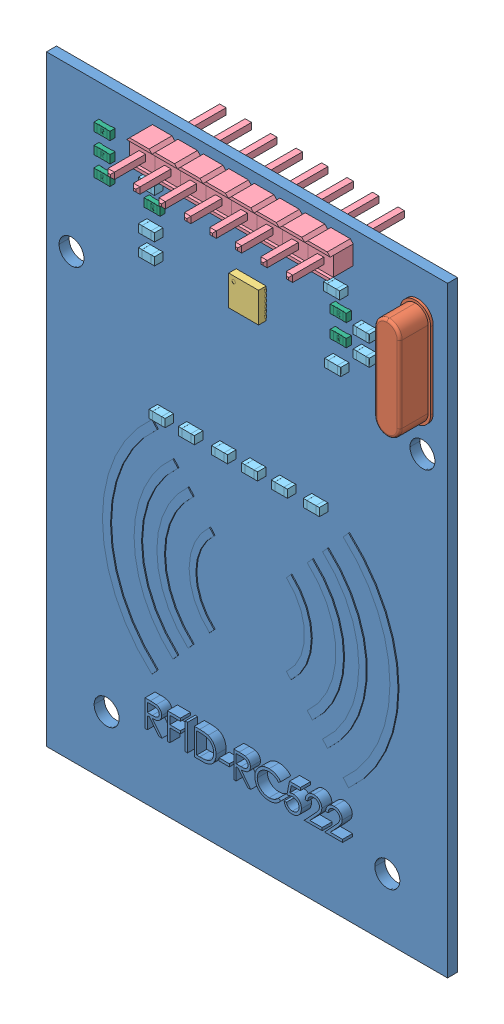
SolidWorks assembly RFID.STEP, configuration Default. Lengths in mm.
Overall size (40 60 11.55).
23 component instances, 6 part files, 0 mates.
Components (placement in the parent):
- Part1^RFID.STEP-1: Part1^RFID.STEP [Default] at (-16.3439 30.7712 59.45) size (40 60 2) (virtual)
- Part10^RFID.STEP-1: Part10^RFID.STEP [Default] at (20.709 20.1029 60.45) x (0 1 0) z (0 0 1) size (10.67 3.05 5.63) (virtual)
- User Library-S-PWSON-N12^RFID.STEP-1: User Library-S-PWSON-N12^RFID.STEP [Default] at (4.1233 20.047 60.45) x (1 0 0) z (0 -1 0) size (3 0.8 3) (virtual)
- User Library-Header_Male_8Pin^RFID.STEP-1: User Library-Header_Male_8Pin^RFID.STEP [Default] at (12.9823 28.5305 62.74) x (-1 0 0) z (0 0 -1) size (20.33 2.5 11.55) (virtual)
- User Library-SMD Ceramic Capacitors_0603 (1608)_CH.STEP-1: User Library-SMD Ceramic Capacitors_0603 (1608)_CH.STEP [Default] at (-3.9959 5.9247 60.9127) size (1.68 0.88 0.93)
- User Library-SMD Ceramic Capacitors_0603 (1608)_CH.STEP-2: User Library-SMD Ceramic Capacitors_0603 (1608)_CH.STEP [Default] at (-1.0806 5.9034 60.9127) size (1.68 0.88 0.93)
- User Library-SMD Ceramic Capacitors_0603 (1608)_CH.STEP-3: User Library-SMD Ceramic Capacitors_0603 (1608)_CH.STEP [Default] at (2.2282 5.9089 60.9127) size (1.68 0.88 0.93)
- User Library-SMD Ceramic Capacitors_0603 (1608)_CH.STEP-4: User Library-SMD Ceramic Capacitors_0603 (1608)_CH.STEP [Default] at (5.214 5.921 60.9127) size (1.68 0.88 0.93)
- User Library-SMD Ceramic Capacitors_0603 (1608)_CH.STEP-5: User Library-SMD Ceramic Capacitors_0603 (1608)_CH.STEP [Default] at (8.193 5.9188 60.9127) size (1.68 0.88 0.93)
- User Library-SMD Ceramic Capacitors_0603 (1608)_CH.STEP-6: User Library-SMD Ceramic Capacitors_0603 (1608)_CH.STEP [Default] at (11.3855 5.9271 60.9127) size (1.68 0.88 0.93)
- User Library-SMD Ceramic Capacitors_0603 (1608)_CH.STEP-7: User Library-SMD Ceramic Capacitors_0603 (1608)_CH.STEP [Default] at (16.3593 23.3789 60.9127) size (1.68 0.88 0.93)
- User Library-SMD Ceramic Capacitors_0603 (1608)_CH.STEP-8: User Library-SMD Ceramic Capacitors_0603 (1608)_CH.STEP [Default] at (16.3593 21.3117 60.9127) size (1.68 0.88 0.93)
- User Library-SMD Ceramic Capacitors_0603 (1608)_CH.STEP-9: User Library-SMD Ceramic Capacitors_0603 (1608)_CH.STEP [Default] at (13.4136 25.6528 60.9127) size (1.68 0.88 0.93)
- User Library-SMD Ceramic Capacitors_0603 (1608)_CH.STEP-10: User Library-SMD Ceramic Capacitors_0603 (1608)_CH.STEP [Default] at (13.517 19.0895 60.9127) size (1.68 0.88 0.93)
- Part8^RFID.STEP-1: Part8^RFID.STEP [Default] at (13.517 23.4826 60.704) size (1.6 0.81 0.51) (virtual)
- Part8^RFID.STEP-2: Part8^RFID.STEP [Default] at (13.517 21.3121 60.704) size (1.6 0.81 0.51) (virtual)
- User Library-SMD Ceramic Capacitors_0603 (1608)_CH.STEP-11: User Library-SMD Ceramic Capacitors_0603 (1608)_CH.STEP [Default] at (-5.0547 25.4542 60.9127) size (1.68 0.88 0.93)
- User Library-SMD Ceramic Capacitors_0603 (1608)_CH.STEP-12: User Library-SMD Ceramic Capacitors_0603 (1608)_CH.STEP [Default] at (-5.0547 21.4355 60.9127) size (1.68 0.88 0.93)
- User Library-SMD Ceramic Capacitors_0603 (1608)_CH.STEP-13: User Library-SMD Ceramic Capacitors_0603 (1608)_CH.STEP [Default] at (-5.0547 19.367 60.9127) size (1.68 0.88 0.93)
- Part8^RFID.STEP-3: Part8^RFID.STEP [Default] at (-5.0547 23.3861 60.704) size (1.6 0.81 0.51) (virtual)
- Part8^RFID.STEP-4: Part8^RFID.STEP [Default] at (-10.0418 25.4159 60.704) size (1.6 0.81 0.51) (virtual)
- Part8^RFID.STEP-5: Part8^RFID.STEP [Default] at (-10.0625 23.4569 60.704) size (1.6 0.81 0.51) (virtual)
- Part8^RFID.STEP-6: Part8^RFID.STEP [Default] at (-10.0541 27.4204 60.704) size (1.6 0.81 0.51) (virtual)
